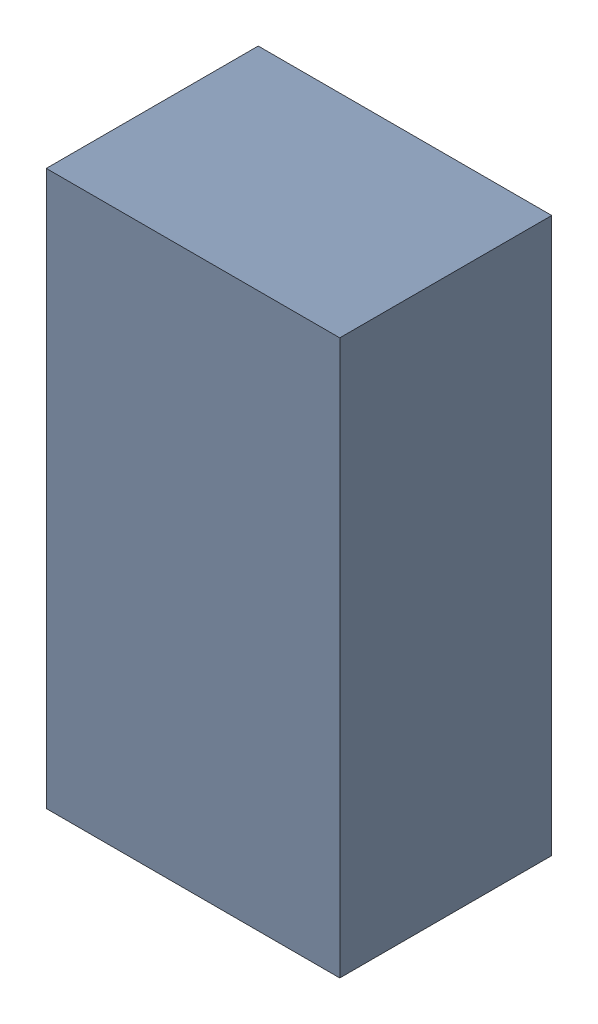
SolidWorks assembly C203, configuration Standard. Lengths in mm.
Overall size (1.8 3.4 1.3).
2 component instances, 1 part files, 0 mates.
Components (placement in the parent):
- 885541968-1: 885541968 [Standard] at (17.29 12.66 0) size (1.8 3.4 1.3)
  - Extruded_30-1: Extruded_30 [Standard] at origin size (1.8 3.4 1.3)
